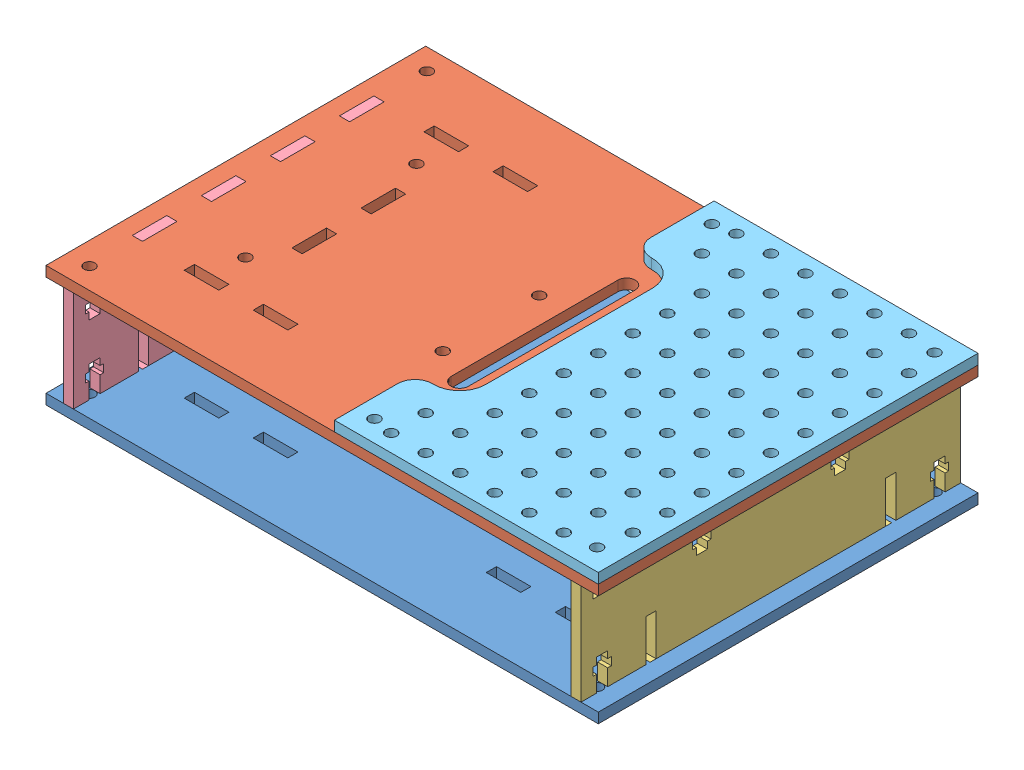
SolidWorks assembly Complete Assembly, configuration Default. Lengths in mm.
Overall size (160 37.98 110).
5 component instances, 5 part files, 13 mates.
Components (placement in the parent):
- Bottom Plate-1: Bottom Plate [Default] at (48.3262 94.8192 120.2186) size (160 2.95 110)
- Top Plate-1: Top Plate [Default] at (48.3262 126.8992 120.2186) size (160 2.95 110)
- Front Sheet-1: Front Sheet [Default] at (119.8805 79.4738 148.8663) x (1 0 0) z (0 1 0) size (2.95 110 35.03)
- Back Sheet-1: Back Sheet [Default] at (-23.3075 74.3164 144.2747) x (1 0 0) z (0 1 0) size (2.95 110 35.03)
- Mount Plate-1: Mount Plate [Default] at (48.3262 129.8492 120.2186) x (1 0 0) z (0 1 0) size (76.44 110 2.95)
Mates (geometry in assembly coordinates):
- Coincident1: coincident anti-aligned: plane of Bottom Plate-1 through (48.3262 97.7692 120.2186) normal (0 1 0); plane of Front Sheet-1 through (48.3262 97.7692 120.2186) normal (0 -1 0)
- Coincident2: coincident anti-aligned: plane of Bottom Plate-1 through (123.3262 94.8192 135.2186) normal (-1 0 0); plane of Front Sheet-1 through (123.3262 236.9387 175.2186) normal (1 0 0)
- Coincident3: coincident anti-aligned: plane of Bottom Plate-1 through (120.3762 94.8192 85.2186) normal (0 0 1); plane of Front Sheet-1 through (120.3762 84.3931 85.2186) normal (0 0 -1)
- Coincident4: coincident anti-aligned: plane of Top Plate-1 through (48.3262 126.8992 120.2186) normal (0 -1 0); plane of Front Sheet-1 through (48.3262 126.8992 120.2186) normal (0 1 0)
- Coincident5: coincident aligned: plane of Top Plate-1 through (-31.6738 129.8492 65.2186) normal (0 0 -1); plane of Front Sheet-1 through (123.3262 236.9387 65.2186) normal (0 0 -1)
- Coincident6: coincident aligned: plane of Bottom Plate-1 through (128.3262 97.7692 65.2186) normal (1 0 0); plane of Top Plate-1 through (128.3262 129.8492 65.2186) normal (1 0 0)
- Coincident7: coincident anti-aligned: plane of Bottom Plate-1 through (48.3262 97.7692 120.2186) normal (0 1 0); plane of Back Sheet-1 through (-98.7238 97.7692 120.2186) normal (0 -1 0)
- Coincident8: coincident anti-aligned: plane of Bottom Plate-1 through (-26.6738 94.8192 85.2186) normal (1 0 0); plane of Back Sheet-1 through (-26.6738 236.9387 175.2186) normal (-1 0 0)
- Coincident9: coincident aligned: plane of Bottom Plate-1 through (-31.6738 97.7692 65.2186) normal (0 0 -1); plane of Back Sheet-1 through (-23.7238 236.9387 65.2186) normal (0 0 -1)
- InPlace1: in place: plane of ? through (48.3262 129.3492 120.2186) normal (0 1 0); plane of ? through (0 129.3492 0) normal (0 1 0); moOrthogonalPlaneRef_w of ? through (48.3262 129.3492 120.2186) normal (0 1 0); plane of ? through (0 129.3492 0) normal (0 0 -1); plane of ? through (48.3262 129.3492 120.2186) normal (0 1 0); plane of ? through (0 129.3492 0) normal (1 0 0); plane of Top Plate-1 through (48.3262 129.8492 120.2186) normal (0 1 0); unknown of Mount Plate-1
- Coincident10: coincident aligned: plane of Top Plate-1; plane of Mount Plate-1
- Coincident11: coincident aligned: moOrthogonalPlaneRef_w of Top Plate-1 through (48.3262 129.8492 120.2186) normal (0 0 -1); plane of Mount Plate-1 through (48.3262 129.8492 120.2186) normal (0 0 -1)
- Coincident12: coincident anti-aligned: moOrthogonalPlaneRef_w of Top Plate-1 through (48.3262 129.8492 120.2186) normal (-1 0 0); plane of Mount Plate-1 through (48.3262 129.8492 120.2186) normal (1 0 0)
